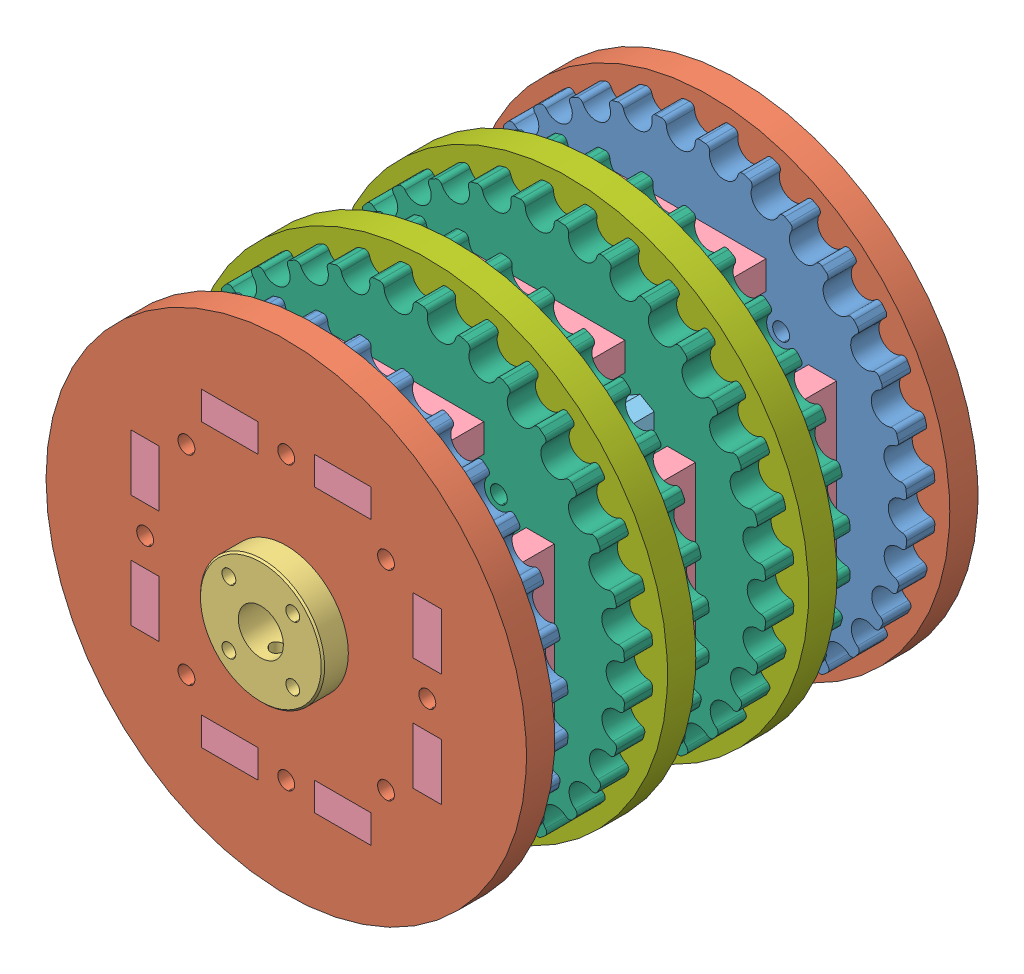
SolidWorks assembly LaserCut-Sprocket, configuration Default. Lengths in mm.
Overall size (85.14 85.14 89).
22 component instances, 7 part files, 82 mates.
Components (placement in the parent):
- Laser-Sprocket-1: Laser-Sprocket [Default] at (13.4163 43.2518 68.8684) size (79.85 79.85 5)
- Laser-Sprocket-Flange-1: Laser-Sprocket-Flange [Default] at (13.4163 43.2518 73.8684) size (85.13 85.13 5)
- MotorHub-2: MotorHub [Default] at (13.4163 43.2518 70.3684) x (0.707107 0.707107 0) z (0.707107 -0.707107 0) size (22 13 22)
- Laser-Sprocket-Spacer-1: Laser-Sprocket-Spacer [Default] at (38.3862 15.7518 33.5597) size (30 5 80)
- Hex-Spacer-10mm-1: Hex-Spacer-10mm [Default] at (36.2622 23.5574 33.8684) x (0.5 -0.866025 0) z (-0.866025 -0.5 0) size (5 10 5.77)
- Hex-Spacer-10mm-2: Hex-Spacer-10mm [Default] at (25.5188 48.7357 33.8684) x (0.5 0.866025 0) z (0.866025 -0.5 0) size (5 10 5.77)
- Hex-Spacer-10mm-3: Hex-Spacer-10mm [Default] at (-9.4336 98.3021 58.8684) x (-0.5 0.866025 0) z (0.866025 0.5 0) size (5 10 5.77)
- Hex-Spacer-10mm-4: Hex-Spacer-10mm [Default] at (1.3144 48.7397 68.8684) x (-0.5 0.866025 0) z (-0.866025 -0.5 0) size (5 10 5.77)
- Laser-Sprocket-Spacer-2: Laser-Sprocket-Spacer [Default] at (38.3862 65.7518 33.5597) size (30 5 80)
- Laser-Sprocket-Spacer-3: Laser-Sprocket-Spacer [Default] at (40.9163 68.2217 33.5597) x (0 1 0) z (0 0 1) size (30 5 80)
- Laser-Sprocket-Spacer-4: Laser-Sprocket-Spacer [Default] at (-9.0837 68.2217 33.5597) x (0 1 0) z (0 0 1) size (30 5 80)
- Laser-Sprocket-Central-3: Laser-Sprocket-Central [Default] at (13.4163 43.2518 53.8684) size (79.85 79.85 5)
- Laser-Sprocket-Flange-Internal-1: Laser-Sprocket-Flange-Internal [Default] at (13.4146 43.2501 48.8684) x (1 -0.000132 0) z (0 0 1) size (85.13 85.13 5)
- Laser-Sprocket-Central-4: Laser-Sprocket-Central [Default] at (13.4163 43.2518 43.8684) size (79.85 79.85 5)
- Laser-Sprocket-Central-5: Laser-Sprocket-Central [Default] at (13.4163 43.2518 28.8684) size (79.85 79.85 5)
- Laser-Sprocket-Flange-Internal-2: Laser-Sprocket-Flange-Internal [Default] at (13.4146 43.2501 23.8684) x (1 0.000132 0) z (0 0 1) size (85.13 85.13 5)
- Laser-Sprocket-Central-6: Laser-Sprocket-Central [Default] at (13.4163 43.2518 18.8684) x (1 0.000264 0) z (0 0 1) size (79.85 79.85 5)
- Hex-Spacer-10mm-5: Hex-Spacer-10mm [Default] at (60.8741 48.7404 8.8684) x (0.5 0.866025 0) z (0.866025 -0.5 0) size (5 10 5.77)
- Hex-Spacer-10mm-6: Hex-Spacer-10mm [Default] at (25.5141 84.091 8.8684) x (0.5 0.866025 0) z (0.866025 -0.5 0) size (5 10 5.77)
- Laser-Sprocket-3: Laser-Sprocket [Default] at (13.4146 43.2501 3.8684) x (1 0.000132 0) z (0 0 1) size (79.85 79.85 5)
- Laser-Sprocket-Flange-3: Laser-Sprocket-Flange [Default] at (13.4146 43.2501 -1.1316) x (1 0.000132 0) z (0 0 1) size (85.13 85.13 5)
- MotorHub-4: MotorHub [Default] at (13.4146 43.2501 7.3684) x (-0.7072 0.707014 0) z (-0.707014 -0.7072 0) size (22 13 22)
Mates (geometry in assembly coordinates):
- Coincidente1: coincident aligned: circle of Laser-Sprocket-1; circle of Laser-Sprocket-Flange-1
- Concentrico1: concentric aligned: circle of Laser-Sprocket-1; circle of Laser-Sprocket-Flange-1
- Coincidente5: coincident aligned: circle of ?; circle of ?
- Concentrico7: concentric aligned: circle of ?; circle of ?
- Concentrico8: concentric aligned: circle of ?; circle of ?
- Concentrico9: concentric anti-aligned: circle of ?; circle of ?
- Coincidente6: coincident anti-aligned: plane of ? through (13.4163 54.2518 23.8684) normal (0 0 1); plane of ? through (13.4163 43.2518 23.8684) normal (0 0 -1)
- Concentrico10: concentric anti-aligned: circle of Laser-Sprocket-1; circle of ?
- Concentrico11: concentric aligned: circle of Laser-Sprocket-Flange-1; circle of ?
- Coincidente8: coincident anti-aligned: plane of Laser-Sprocket-1 through (28.4163 20.7518 73.8684) normal (-1 0 0); plane of Laser-Sprocket-Spacer-1 through (28.4163 20.7518 -1.1316) normal (1 0 0)
- Coincidente10: coincident anti-aligned: plane of Laser-Sprocket-1 through (8.4163 20.7518 73.8684) normal (0 -1 0); plane of Laser-Sprocket-Spacer-1 through (38.3862 20.7518 33.5597) normal (0 1 0)
- Coincidente11: coincident aligned: plane of Laser-Sprocket-Flange-1 through (13.4163 43.2518 78.8684) normal (0 0 1); plane of Laser-Sprocket-Spacer-1 through (-1.5837 20.7518 78.8684) normal (0 0 1)
- Coincidente12: coincident aligned: plane of ? through (13.4163 43.2518 18.8684) normal (0 0 -1); plane of Laser-Sprocket-Spacer-1 through (-1.5837 20.7518 18.8684) normal (0 0 -1)
- Coincidente13: coincident anti-aligned: plane of Laser-Sprocket-Spacer-1 through (38.3862 15.7518 33.5597) normal (0 -1 0); plane of Laser-Sprocket-Central-4 through (-1.5837 15.7518 48.8684) normal (0 1 0)
- Coincidente14: coincident anti-aligned: plane of Laser-Sprocket-Spacer-1 through (-1.5837 20.7518 18.8684) normal (-1 0 0); plane of Laser-Sprocket-Central-4 through (-1.5837 15.7518 48.8684) normal (1 0 0)
- Coincidente15: coincident aligned: circle of Laser-Sprocket-Central-4; circle of Hex-Spacer-10mm-1
- Parallelo1: parallel anti-aligned: line of Laser-Sprocket-Central-4 through (-1.5837 65.7518 43.8684) axis (1 0 0); line of Hex-Spacer-10mm-1 through (32.5333 63.4301 28.8684) axis (-1 0 0)
- Parallelo2: parallel anti-aligned: line of Laser-Sprocket-Central-4 through (-1.5837 65.7518 43.8684) axis (1 0 0); line of Hex-Spacer-10mm-3 through (-2.8174 63.4301 53.8684) axis (-1 0 0)
- Parallelo3: parallel anti-aligned: line of Laser-Sprocket-Central-4 through (-1.5837 65.7518 43.8684) axis (1 0 0); line of Hex-Spacer-10mm-2 through (-2.8174 28.0701 28.8684) axis (-1 0 0)
- Coincidente20: coincident aligned: circle of Laser-Sprocket-Central-4; circle of Hex-Spacer-10mm-2
- Parallelo5: parallel aligned: line of Laser-Sprocket-Central-4 through (-1.5837 65.7518 48.8684) axis (1 0 0); line of Hex-Spacer-10mm-4 through (29.6465 28.0701 53.8684) axis (1 0 0)
- Coincidente24: coincident anti-aligned: plane of ? through (13.4163 43.2518 28.8684) normal (0 0 1); plane of Hex-Spacer-10mm-1 through (54.2556 31.1505 28.8684) normal (0 0 -1)
- Coincidente25: coincident aligned: line of Laser-Sprocket-Central-4 through (-1.5837 65.7518 48.8684) axis (1 0 0); line of ? through (-1.5837 65.7518 48.8684) axis (1 0 0)
- Coincidente26: coincident aligned: line of Laser-Sprocket-Central-4 through (28.4163 20.7518 48.8684) axis (-1 0 0); line of ? through (28.4163 20.7518 48.8684) axis (-1 0 0)
- Coincidente27: coincident aligned: line of Laser-Sprocket-Central-4 through (-14.0837 58.2518 48.8684) axis (0 -1 0); line of ? through (-14.0837 58.2518 48.8684) axis (0 -1 0)
- Coincidente28: coincident aligned: circle of Hex-Spacer-10mm-3; circle of ?
- Coincidente29: coincident anti-aligned: circle of Hex-Spacer-10mm-4; circle of ?
- Coincidente30: coincident aligned: plane of ? through (13.4163 43.2518 18.8684) normal (0 0 -1); plane of Laser-Sprocket-Spacer-2 through (-1.5837 70.7518 18.8684) normal (0 0 -1)
- Coincidente31: coincident anti-aligned: plane of ? through (28.4163 70.7518 23.8684) normal (-1 0 0); plane of Laser-Sprocket-Spacer-2 through (28.4163 70.7518 18.8684) normal (1 0 0)
- Coincidente32: coincident anti-aligned: plane of ? through (28.4163 65.7518 23.8684) normal (0 1 0); plane of Laser-Sprocket-Spacer-2 through (38.3862 65.7518 33.5597) normal (0 -1 0)
- Coincidente33: coincident aligned: plane of ? through (13.4163 43.2518 18.8684) normal (0 0 -1); plane of Laser-Sprocket-Spacer-3 through (35.9163 28.2518 18.8684) normal (0 0 -1)
- Coincidente34: coincident anti-aligned: plane of ? through (40.9163 48.2518 23.8684) normal (0 1 0); plane of Laser-Sprocket-Spacer-3 through (35.9163 48.2518 18.8684) normal (0 -1 0)
- Coincidente35: coincident anti-aligned: plane of ? through (35.9163 58.2518 23.8684) normal (1 0 0); plane of Laser-Sprocket-Spacer-3 through (35.9163 68.2217 33.5597) normal (-1 0 0)
- Coincidente36: coincident aligned: plane of ? through (13.4163 43.2518 18.8684) normal (0 0 -1); plane of Laser-Sprocket-Spacer-4 through (-14.0837 28.2518 18.8684) normal (0 0 -1)
- Coincidente37: coincident anti-aligned: plane of ? through (-9.0837 58.2518 23.8684) normal (-1 0 0); plane of Laser-Sprocket-Spacer-4 through (-9.0837 68.2217 33.5597) normal (1 0 0)
- Coincidente38: coincident anti-aligned: plane of ? through (-14.0837 48.2518 23.8684) normal (0 1 0); plane of Laser-Sprocket-Spacer-4 through (-14.0837 48.2518 18.8684) normal (0 -1 0)
- Coincidente39: coincident aligned: circle of Laser-Sprocket-1; circle of Hex-Spacer-10mm-3
- Coincidente40: coincident anti-aligned: circle of Laser-Sprocket-1; circle of Hex-Spacer-10mm-4
- Parallelo6: parallel anti-aligned: line of Laser-Sprocket-1 through (40.9163 28.2518 68.8684) axis (0 1 0); line of Hex-Spacer-10mm-4 through (33.594 27.0175 68.8684) axis (0 -1 0)
- Coincidente45: coincident aligned: plane of Laser-Sprocket-Flange-1 through (13.4163 43.2518 78.8684) normal (0 0 1); plane of Laser-Sprocket-Spacer-3 through (35.9163 28.2518 78.8684) normal (0 0 1)
- Coincidente46: coincident aligned: plane of Laser-Sprocket-Flange-1 through (13.4163 43.2518 78.8684) normal (0 0 1); plane of Laser-Sprocket-Spacer-2 through (-1.5837 70.7518 78.8684) normal (0 0 1)
- Coincidente47: coincident aligned: plane of Laser-Sprocket-Flange-1 through (13.4163 43.2518 78.8684) normal (0 0 1); plane of Laser-Sprocket-Spacer-4 through (-14.0837 28.2518 78.8684) normal (0 0 1)
- Coincidente48: coincident anti-aligned: plane of Laser-Sprocket-Flange-1 through (8.4163 70.7518 78.8684) normal (-1 0 0); plane of Laser-Sprocket-Spacer-2 through (8.4163 70.7518 78.8684) normal (1 0 0)
- Coincidente49: coincident anti-aligned: plane of Laser-Sprocket-Flange-1 through (-1.5837 65.7518 78.8684) normal (0 1 0); plane of Laser-Sprocket-Spacer-2 through (38.3862 65.7518 33.5597) normal (0 -1 0)
- Coincidente50: coincident anti-aligned: plane of Laser-Sprocket-Flange-1 through (-9.0837 58.2518 78.8684) normal (-1 0 0); plane of Laser-Sprocket-Spacer-4 through (-9.0837 68.2217 33.5597) normal (1 0 0)
- Coincidente52: coincident anti-aligned: plane of Laser-Sprocket-Flange-1 through (-14.0837 28.2518 78.8684) normal (0 1 0); plane of Laser-Sprocket-Spacer-4 through (-14.0837 28.2518 -1.1316) normal (0 -1 0)
- Coincidente53: coincident anti-aligned: plane of Laser-Sprocket-Flange-1 through (40.9163 38.2518 78.8684) normal (0 -1 0); plane of Laser-Sprocket-Spacer-3 through (35.9163 38.2518 78.8684) normal (0 1 0)
- Coincidente54: coincident anti-aligned: plane of Laser-Sprocket-Flange-1 through (35.9163 28.2518 78.8684) normal (1 0 0); plane of Laser-Sprocket-Spacer-3 through (35.9163 68.2217 33.5597) normal (-1 0 0)
- Coincidente55: coincident anti-aligned: plane of Laser-Sprocket-Spacer-2 through (38.3862 65.7518 33.5597) normal (0 -1 0); plane of Laser-Sprocket-Central-3 through (28.4163 65.7518 58.8684) normal (0 1 0)
- Coincidente56: coincident anti-aligned: plane of Laser-Sprocket-Spacer-3 through (35.9163 68.2217 33.5597) normal (-1 0 0); plane of Laser-Sprocket-Central-3 through (35.9163 28.2518 58.8684) normal (1 0 0)
- Coincidente57: coincident anti-aligned: plane of Hex-Spacer-10mm-4 through (1.3144 48.7397 58.8684) normal (0 0 -1); plane of Laser-Sprocket-Central-3 through (13.4163 43.2518 58.8684) normal (0 0 1)
- Coincidente58: coincident aligned: circle of Laser-Sprocket-Central-3; circle of Laser-Sprocket-Flange-Internal-1
- Coincidente59: coincident aligned: circle of Laser-Sprocket-Central-3; circle of Laser-Sprocket-Flange-Internal-1
- Coincidente60: coincident aligned: circle of Laser-Sprocket-Flange-Internal-1; circle of Laser-Sprocket-Central-4
- Coincidente61: coincident aligned: circle of Laser-Sprocket-Flange-Internal-1; circle of Laser-Sprocket-Central-4
- Coincidente62: coincident aligned: circle of Hex-Spacer-10mm-2; circle of Laser-Sprocket-Central-4
- Coincidente64: coincident aligned: circle of Hex-Spacer-10mm-1; circle of Laser-Sprocket-Central-4
- Coincidente66: coincident aligned: circle of Hex-Spacer-10mm-2; circle of Laser-Sprocket-Central-5
- Coincidente68: coincident aligned: circle of Hex-Spacer-10mm-1; circle of Laser-Sprocket-Central-5
- Coincidente69: coincident aligned: circle of Laser-Sprocket-Central-5; circle of Laser-Sprocket-Flange-Internal-2
- Coincidente70: coincident aligned: circle of Laser-Sprocket-Central-5; circle of Laser-Sprocket-Flange-Internal-2
- Coincidente71: coincident aligned: circle of Laser-Sprocket-Flange-Internal-2; circle of Laser-Sprocket-Central-6
- Coincidente72: coincident aligned: circle of Laser-Sprocket-Flange-Internal-2; circle of Laser-Sprocket-Central-6
- Coincidente73: coincident aligned: circle of Laser-Sprocket-Central-6; circle of Hex-Spacer-10mm-5
- Coincidente75: coincident aligned: circle of Laser-Sprocket-Central-6; circle of Hex-Spacer-10mm-6
- Coincidente77: coincident anti-aligned: plane of Laser-Sprocket-Spacer-1 through (8.4163 20.7518 8.8684) normal (0 0 -1); plane of Laser-Sprocket-3 through (13.4146 43.2501 8.8684) normal (0 0 1)
- Coincidente79: coincident aligned: circle of Hex-Spacer-10mm-6; circle of Laser-Sprocket-3
- Coincidente80: coincident aligned: circle of Hex-Spacer-10mm-5; circle of Laser-Sprocket-3
- Coincidente81: coincident aligned: circle of Laser-Sprocket-3; circle of Laser-Sprocket-Flange-3
- Coincidente82: coincident aligned: circle of Laser-Sprocket-3; circle of Laser-Sprocket-Flange-3
- Concentrico12: concentric aligned: circle of Laser-Sprocket-3; circle of MotorHub-4
- Concentrico13: concentric aligned: circle of Laser-Sprocket-3; circle of MotorHub-4
- Coincidente83: coincident anti-aligned: plane of Laser-Sprocket-3 through (13.4146 43.2501 3.8684) normal (0 0 -1); plane of MotorHub-4 through (5.6354 51.0272 3.8684) normal (0 0 1)
- Parallelo13: parallel aligned: plane of Laser-Sprocket-Spacer-4 through (-14.0837 68.2217 33.5597) normal (-1 0 0); plane of Hex-Spacer-10mm-6 through (-6.7654 62.3688 18.8684) normal (-1 0 0)
- Parallelo14: parallel aligned: plane of Hex-Spacer-10mm-3 through (-6.7614 62.3728 68.8684) normal (-1 0 0); plane of Laser-Sprocket-Spacer-4 through (-14.0837 68.2217 33.5597) normal (-1 0 0)
- Parallelo17: parallel aligned: plane of Hex-Spacer-10mm-2 through (-6.7608 27.0134 43.8684) normal (-1 0 0); plane of Laser-Sprocket-Spacer-4 through (-14.0837 68.2217 33.5597) normal (-1 0 0)
- Parallelo19: parallel aligned: plane of Hex-Spacer-10mm-1 through (33.5899 59.4867 43.8684) normal (1 0 0); plane of Laser-Sprocket-Spacer-3 through (40.9163 68.2217 33.5597) normal (1 0 0)
- Parallelo20: parallel aligned: plane of Hex-Spacer-10mm-4 through (33.594 27.0175 58.8684) normal (1 0 0); plane of Laser-Sprocket-Spacer-3 through (40.9163 68.2217 33.5597) normal (1 0 0)
- Parallelo21: parallel aligned: plane of Laser-Sprocket-Spacer-3 through (40.9163 68.2217 33.5597) normal (1 0 0); plane of Hex-Spacer-10mm-5 through (33.5946 24.1313 18.8684) normal (1 0 0)
- Concentrico14: concentric aligned: circle of Laser-Sprocket-1; circle of MotorHub-2
- Coincidente90: coincident anti-aligned: plane of Laser-Sprocket-1 through (13.4163 43.2518 73.8684) normal (0 0 1); plane of MotorHub-2 through (21.1945 51.0299 73.8684) normal (0 0 -1)
- Concentrico15: concentric aligned: circle of Laser-Sprocket-1; circle of MotorHub-2
